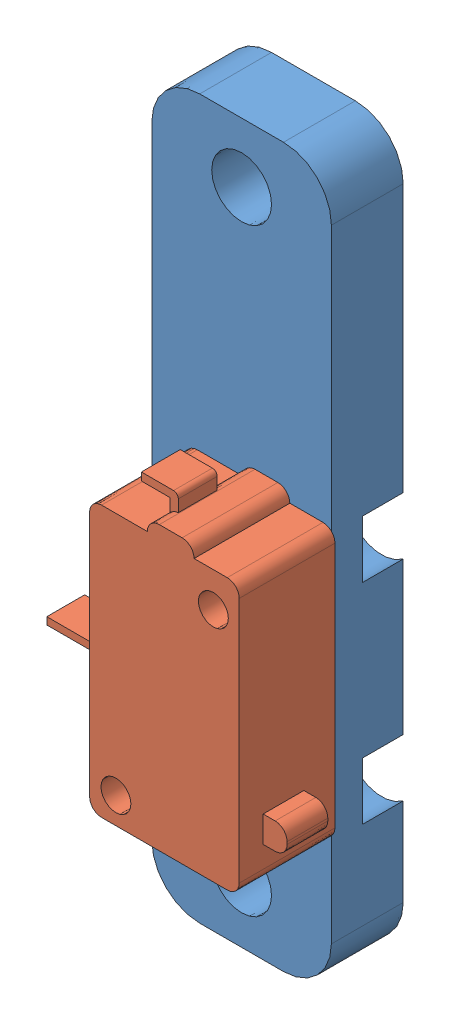
SolidWorks assembly Assem1, configuration Default. Lengths in mm.
Overall size (24.77 76.2 22.16).
2 component instances, 2 part files, 6 mates.
Components (placement in the parent):
- LimitSwitchMount2018-1: LimitSwitchMount2018 [Default] at origin size (19.05 76.2 12)
- 2018 Limit Switch-1: 2018 Limit Switch [Default] at (-10.414 -4.2545 7.62) x (0 -1 0) z (0 0 1) size (31.75 24.77 10.16)
Mates (geometry in assembly coordinates):
- Coincident2: coincident: point of LimitSwitchMount2018-1; point of assembly
- Coincident3: coincident aligned: plane of LimitSwitchMount2018-1 through (0 0 0) normal (0 0 1); plane of assembly
- Coincident4: coincident aligned: plane of LimitSwitchMount2018-1 through (0 0 0) normal (1 0 0); plane of assembly
- Concentric5: concentric: cylinder of LimitSwitchMount2018-1 through (-7.62 -30.1625 0) axis (0 0 -1) radius 1.632; cylinder of 2018 Limit Switch-1 through (-7.62 -30.1625 15.2243) axis (0 0 1) radius 1.5875
- Parallel4: parallel: plane of LimitSwitchMount2018-1 through (-13.97 -47.625 7.62) normal (0 -1 0); plane of 2018 Limit Switch-1 through (-10.414 -32.9565 17.78) normal (0 -1 0)
- Coincident5: coincident anti-aligned: plane of LimitSwitchMount2018-1 through (0 0 7.62) normal (0 0 1); plane of 2018 Limit Switch-1 through (-10.414 -4.2545 7.62) normal (0 0 -1)
